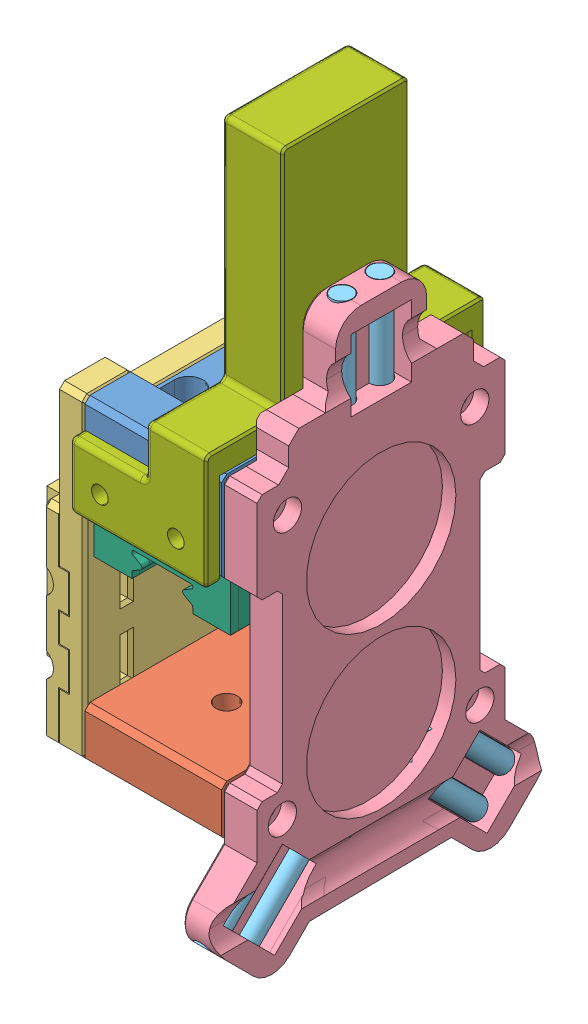
SolidWorks assembly New_Carriage, configuration Default. Lengths in mm.
Overall size (51.82 133.22 64.75).
12 component instances, 7 part files, 30 mates.
Components (placement in the parent):
- top-1: top [Default] at (11.3892 16.4358 2.1658) x (0 1 0) z (0 0 1) size (18 27 49)
- bot-1: bot [Default] at (11.3892 -31.0642 2.1658) x (0 1 0) z (0 0 1) size (10 27 49)
- back-1: back [Default] at (-2.1108 16.4358 70.2658) x (0 -1 0) z (-1 0 0) size (62.5 49 17.5)
- tool_changer_v3_carriage-1: tool_changer_v3_carriage [Default] at (30.8892 -6.2421 36.2158) x (0 0 1) z (-1 0 0) size (64.58 105.62 7.32)
- kinematic_dowel-1: kinematic_dowel [Default] at (27.8892 42.0912 32.4658) size (4 25 4)
- kinematic_dowel-2: kinematic_dowel [Default] at (27.8892 42.0912 39.9658) size (4 25 4)
- kinematic_dowel-3: kinematic_dowel [Default] at (27.8892 -31.5875 66.8645) x (0.940985 0.23932 0.23932) z (-0.338449 0.665377 0.665377) size (4 25 4)
- kinematic_dowel-4: kinematic_dowel [Default] at (27.8892 -36.8908 61.5611) x (0.378708 0.654439 0.654439) z (-0.925516 0.267787 0.267787) size (4 25 4)
- kinematic_dowel-5: kinematic_dowel [Default] at (27.8892 -31.5875 5.5671) x (1 0 0) z (0 -0.707107 0.707107) size (4 25 4)
- kinematic_dowel-6: kinematic_dowel [Default] at (27.8892 -36.8908 10.8704) x (1 0 0) z (0 -0.707107 0.707107) size (4 25 4)
- MGN12H Block-1: MGN12H Block [Default] at (-2.8013 4.152 -227.5171) size (27 10 45.4)
- Cable_chain_mount-1: Cable_chain_mount [Default] at (11.3892 16.4358 11.7158) x (0 -1 0) z (0 0 -1) size (68 27 55.1)
Mates (geometry in assembly coordinates):
- Coincident1: coincident anti-aligned: plane of top-1 through (-2.1108 39.4858 36.2158) normal (-1 0 0); plane of back-1 through (-2.1108 16.4358 70.2658) normal (1 0 0)
- Coincident2: coincident aligned: plane of top-1 through (11.3892 39.4858 36.2158) normal (0 1 0); plane of back-1 through (-7.1108 39.4858 50.7158) normal (0 1 0)
- Coincident3: coincident aligned: plane of top-1 through (11.3892 16.4358 60.7158) normal (0 0 1); plane of back-1 through (-7.1108 -18.0142 60.7158) normal (0 0 1)
- Coincident4: coincident anti-aligned: plane of bot-1 through (-2.1108 -8.0142 36.2158) normal (-1 0 0); plane of back-1 through (-2.1108 16.4358 70.2658) normal (1 0 0)
- Coincident6: coincident aligned: plane of bot-1 through (11.3892 -31.0642 11.7158) normal (0 0 -1); plane of back-1 through (-7.1108 38.4858 11.7158) normal (0 0 -1)
- Coincident7: coincident anti-aligned: plane of bot-1 through (24.8892 -8.0142 36.2158) normal (1 0 0); plane of tool_changer_v3_carriage-1 through (24.8892 -6.2421 36.2158) normal (-1 0 0)
- Concentric1: concentric anti-aligned: cylinder of top-1 through (29.4147 38.4858 54.7158) axis (-1 0 0) radius 1.6; cylinder of tool_changer_v3_carriage-1 through (20.3637 38.4858 54.7158) axis (1 0 0) radius 1.6
- Concentric2: concentric aligned: cylinder of bot-1 through (-6.9191 -13.0142 16.7158) axis (1 0 0) radius 1.7; cylinder of tool_changer_v3_carriage-1 through (20.3637 -13.0142 16.7158) axis (1 0 0) radius 1.6
- Concentric3: concentric anti-aligned: cylinder of tool_changer_v3_carriage-1 through (27.8892 42.0912 32.4658) axis (0 1 0) radius 2.1; cylinder of kinematic_dowel-1 through (27.8892 67.0912 32.4658) axis (0 -1 0) radius 2
- Coincident8: coincident aligned: plane of tool_changer_v3_carriage-1 through (24.8892 67.0912 36.2158) normal (0 1 0); plane of kinematic_dowel-1 through (27.8892 67.0912 32.4658) normal (0 1 0)
- Concentric4: concentric anti-aligned: cylinder of tool_changer_v3_carriage-1 through (27.8892 42.0912 39.9658) axis (0 1 0) radius 2.1; cylinder of kinematic_dowel-2 through (27.8892 67.0912 39.9658) axis (0 -1 0) radius 2
- Coincident9: coincident aligned: plane of tool_changer_v3_carriage-1 through (24.8892 67.0912 36.2158) normal (0 1 0); plane of kinematic_dowel-2 through (27.8892 67.0912 39.9658) normal (0 1 0)
- Concentric5: concentric aligned: cylinder of tool_changer_v3_carriage-1 through (27.8892 50.2577 87.4123) axis (0 -0.707107 -0.707107) radius 2.1; cylinder of kinematic_dowel-5 through (27.8892 -13.9098 23.2447) axis (0 -0.707107 -0.707107) radius 2
- Coincident10: coincident aligned: plane of tool_changer_v3_carriage-1 through (24.8892 -34.2391 8.2187) normal (0 -0.707107 -0.707107); plane of kinematic_dowel-5 through (27.8892 -31.5875 5.5671) normal (0 -0.707107 -0.707107)
- Concentric6: concentric aligned: cylinder of tool_changer_v3_carriage-1 through (27.8892 44.9544 92.7156) axis (0 -0.707107 -0.707107) radius 2.1; cylinder of kinematic_dowel-6 through (27.8892 -19.2131 28.548) axis (0 -0.707107 -0.707107) radius 2
- Coincident11: coincident aligned: plane of tool_changer_v3_carriage-1 through (24.8892 -34.2391 8.2187) normal (0 -0.707107 -0.707107); plane of kinematic_dowel-6 through (27.8892 -36.8908 10.8704) normal (0 -0.707107 -0.707107)
- Concentric7: concentric aligned: cylinder of tool_changer_v3_carriage-1 through (27.8892 50.2577 -14.9808) axis (0 -0.707107 0.707107) radius 2.1; cylinder of kinematic_dowel-3 through (27.8892 -13.9098 49.1868) axis (0 -0.707107 0.707107) radius 2
- Coincident12: coincident aligned: plane of tool_changer_v3_carriage-1 through (24.8892 -34.2391 64.2128) normal (0 -0.707107 0.707107); plane of kinematic_dowel-3 through (27.8892 -31.5875 66.8645) normal (0 -0.707107 0.707107)
- Concentric8: concentric aligned: cylinder of tool_changer_v3_carriage-1 through (27.8892 44.9544 -20.2841) axis (0 -0.707107 0.707107) radius 2.1; cylinder of kinematic_dowel-4 through (27.8892 -19.2131 43.8835) axis (0 -0.707107 0.707107) radius 2
- Coincident13: coincident aligned: plane of tool_changer_v3_carriage-1 through (24.8892 -34.2391 64.2128) normal (0 -0.707107 0.707107); plane of kinematic_dowel-4 through (27.8892 -36.8908 61.5611) normal (0 -0.707107 0.707107)
- Width1: width aligned: plane of Belt_clamp_new-1 through (-14.6538 12.1908 59.7158) normal (0 0 1); plane of back-1 through (-10.1108 24.5908 52.7158) normal (0 0 -1); plane of Belt_clamp_new-1 through (-2.1108 16.4358 51.7158) normal (0 0 1); plane of back-1 through (-7.1108 -18.0142 60.7158) normal (0 0 1)
- Width2: width anti-aligned: plane of Belt_clamp_new-1 through (-7.1108 15.9908 8.7538) normal (0 1 0); plane of back-1 through (-5.4108 -10.5192 8.7538) normal (0 -1 0); plane of Belt_clamp_new-1 through (-2.1108 13.2358 70.2658) normal (0 -1 0); plane of back-1 through (-2.1108 -7.7642 70.2658) normal (0 1 0)
- Coincident14: coincident anti-aligned: plane of back-1 through (-7.1108 16.4358 70.2658) normal (-1 0 0); plane of Belt_clamp_new-1 through (-7.1108 8.3908 8.7538) normal (1 0 0)
- Width3: width anti-aligned: plane of MGN12H Block-1 through (5.3907 9.4284 58.9158) normal (0 0 1); plane of top-1 through (5.3907 9.4284 13.5158) normal (0 0 -1); plane of MGN12H Block-1 through (11.3892 16.4358 11.7158) normal (0 0 -1); plane of top-1 through (11.3892 16.4358 60.7158) normal (0 0 1)
- Width4: width anti-aligned: plane of MGN12H Block-1 through (-2.1108 9.4284 13.5158) normal (-1 0 0); plane of back-1 through (24.8892 9.4284 13.5158) normal (1 0 0); plane of MGN12H Block-1 through (-2.1108 16.4358 70.2658) normal (1 0 0); plane of tool_changer_v3_carriage-1 through (24.8892 -6.2421 36.2158) normal (-1 0 0)
- Coincident15: coincident anti-aligned: plane of top-1 through (11.3892 26.4858 36.2158) normal (0 -1 0); plane of MGN12H Block-1 through (5.3892 26.4858 13.5158) normal (0 1 0)
- InPlace1: in place: plane of top-1 through (11.3892 16.4358 11.7158) normal (0 0 -1); plane of ? through (0 0 11.7158) normal (0 0 -1); moOrthogonalPlaneRef_w of top-1 through (11.3892 16.4358 11.7158) normal (0 0 -1); plane of ? through (0 0 11.7158) normal (0 1 0); plane of top-1 through (11.3892 16.4358 11.7158) normal (0 0 -1); plane of ? through (0 0 11.7158) normal (-1 0 0); plane of top-1 through (11.3892 16.4358 11.7158) normal (0 0 -1); unknown of Cable_chain_mount-1
- Coincident16: coincident aligned: plane of ?; plane of ?
- Coincident17: coincident aligned: moOrthogonalPlaneRef_w of top-1 through (11.3892 16.4358 11.7158) normal (-1 0 0); plane of Part3^New_Carriage-1 through (11.3892 16.4358 11.7158) normal (-1 0 0)
- Coincident18: coincident anti-aligned: moOrthogonalPlaneRef_w of top-1 through (11.3892 16.4358 11.7158) normal (0 1 0); plane of Part3^New_Carriage-1 through (11.3892 16.4358 11.7158) normal (0 -1 0)
